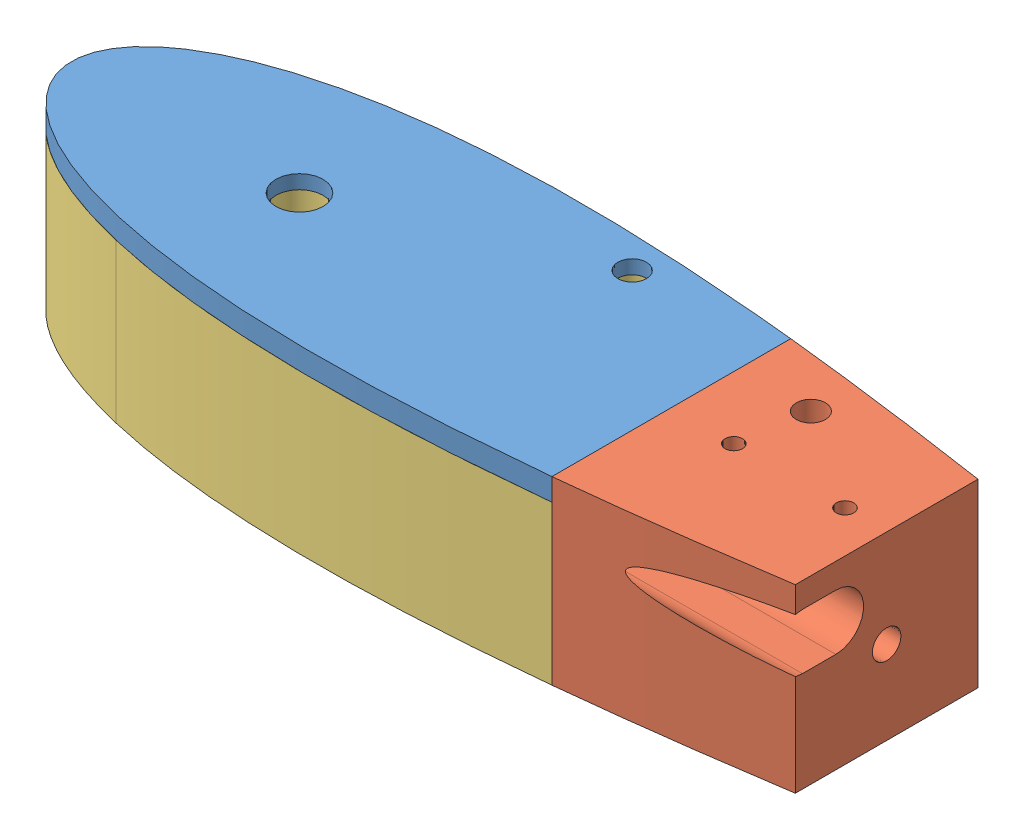
SolidWorks assembly Control Box, configuration Default. Lengths in mm.
Overall size (424.95 82.55 211.81).
3 component instances, 3 part files, 6 mates.
Components (placement in the parent):
- MAST HALF FINAL Cover-1: MAST HALF FINAL Cover [Default] at (-101.2218 1803.4 -9.0672) x (1 0 0) z (0 -1 0) size (371.53 211.81 10.16)
- TRIM TAB HALF FINAL-1: TRIM TAB HALF FINAL [Default] at (-101.2218 1803.4 -9.0672) x (1 0 0) z (0 -1 0) size (102.16 109.14 82.55)
- MAST HALF FINAL-1: MAST HALF FINAL [Default] at (-101.2218 1803.4 -9.0672) x (1 0 0) z (0 -1 0) size (279.71 147.64 63.5)
Mates (geometry in assembly coordinates):
- Coincident104: coincident aligned: circle of MAST HALF FINAL-1; cylinder of MAST HALF FINAL Cover-1 through (2.9174 1803.4 -9.0672) axis (0 -1 0) radius 10.795
- Coincident105: coincident aligned: plane of MAST HALF FINAL-1 through (172.8395 1727.2 61.4996) normal (1 0 0); plane of MAST HALF FINAL Cover-1 through (172.8395 1727.2 61.4996) normal (1 0 0)
- LimitDistance4: limit distance = 0 mm anti-aligned: plane of MAST HALF FINAL Cover-1 through (-101.2218 1803.4 -9.0672) normal (0 -1 0); plane of MAST HALF FINAL-1 through (-101.2218 1803.4 -9.0672) normal (0 1 0)
- LimitDistance2: limit distance = 0 mm anti-aligned: plane of MAST HALF FINAL-1 through (172.8395 1727.2 61.4996) normal (1 0 0); plane of TRIM TAB HALF FINAL-1 through (172.8395 1727.2 63.1174) normal (-1 0 0)
- Concentric75: concentric aligned: cylinder of MAST HALF FINAL-1 through (164.5415 1765.3 -9.0672) axis (1 0 0) radius 6.6675; cylinder of TRIM TAB HALF FINAL-1 through (164.5415 1765.3 -9.0672) axis (1 0 0) radius 6.5405
- Coincident152: coincident anti-aligned: plane of MAST HALF FINAL-1 through (172.8395 1727.2 61.4996) normal (1 0 0); plane of TRIM TAB HALF FINAL-1 through (172.8395 1727.2 63.1174) normal (-1 0 0)
